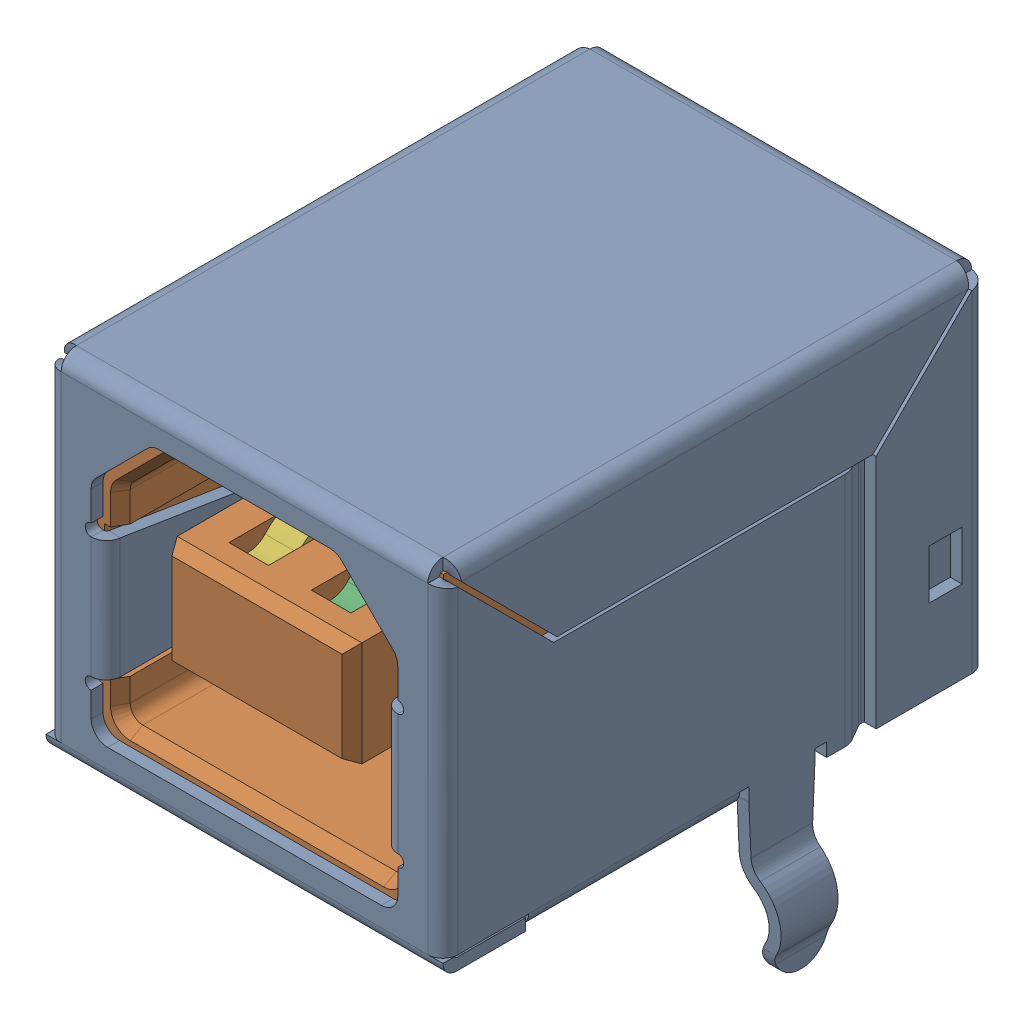
SolidWorks assembly USB type b, configuration Default. Lengths in mm.
Overall size (13.72 15.2 16.5).
6 component instances, 4 part files, 0 mates.
Components (placement in the parent):
- USB SHELL-1: USB SHELL [Default] at origin size (13.72 15.2 16.5)
- USB core-1: USB core [Default] at origin size (11.3 10.68 15.75)
- usb top contact-1: usb top contact [Default] at (1.25 6.09 -0.38) size (1 9.67 13.76)
- usb btm contact-1: usb btm contact [Default] at (1.25 4.41 -0.38) size (1 6.84 11.76)
- usb btm contact-2: usb btm contact [Default] at (-1.25 4.41 -0.38) size (1 6.84 11.76)
- usb top contact-2: usb top contact [Default] at (-1.25 6.09 -0.38) size (1 9.67 13.76)
